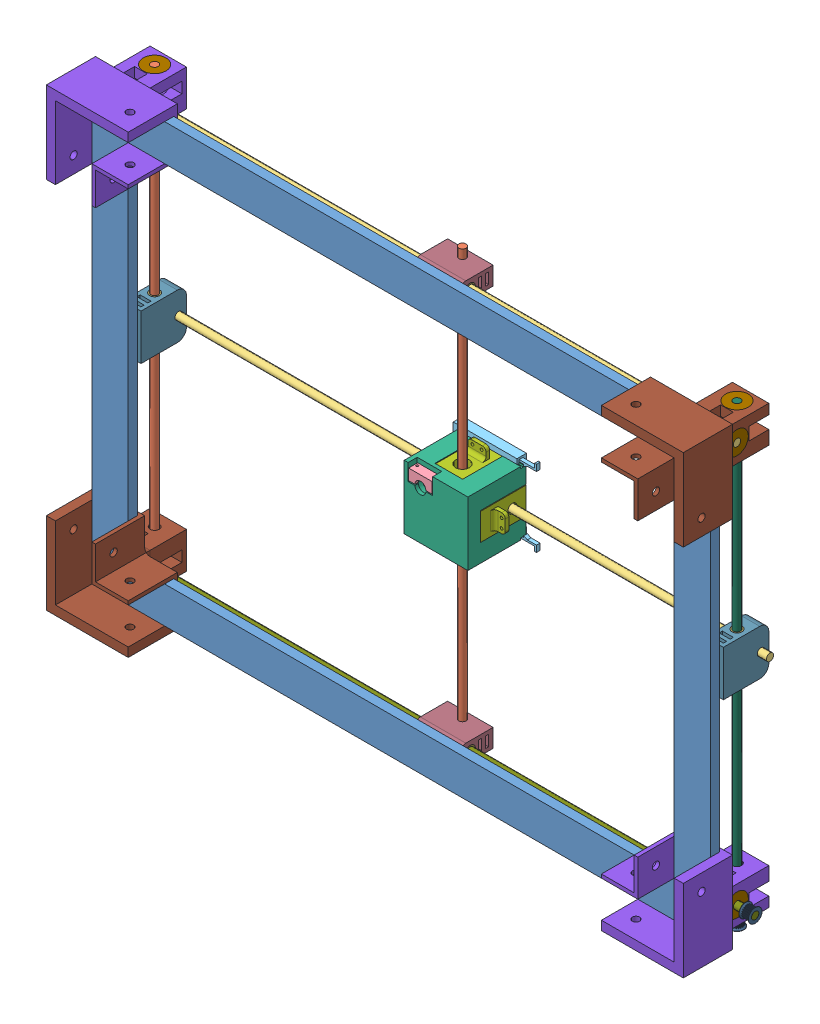
SolidWorks assembly Assemblage_XY, configuration Défaut. Lengths in mm.
Overall size (711.34 510 125.29).
50 component instances, 16 part files, 70 mates.
Components (placement in the parent):
- Cadre_XY-1: Cadre_XY [Défaut] at (379.0068 -247.2078 675) size (680 480 10)
- AXE_8X480-2: AXE_8X480 [Défaut] at (-280.9932 -247.2078 636) x (0.987721 0 0.156231) z (0 1 0) size (8 8 480)
- AXE_8X680-1: AXE_8X680 [Défaut] at (379.0068 212.7922 656) x (0 0.013067 0.999915) z (-1 0 0) size (8 8 680)
- AXE_8X480-3: AXE_8X480 [Défaut] at (60.9851 232.7922 639.7) x (0.999527 0 0.030742) z (0 -1 0) size (8 8 480)
- AXE_8X680-3: AXE_8X680 [Défaut] at (-300.9932 -9.5149 619.7) x (0 -0.696158 -0.717888) z (1 0 0) size (8 8 680)
- P3DMIPC-Tête_complete-1: P3DMIPC-Tête_complete [Défaut] at (16.7924 3.8551 635.2981) x (0 1 0) z (1 0 0) size (94 69 96.37)
  - P3DMIPC-Clip_Buse_E3D-1: P3DMIPC-Clip_Buse_E3D [Défaut] at (17.0518 23.4109 40.0035) x (1 0 0) z (0 1 0) size (12 26 10)
  - P3DMIPC-Clip_tête-1: P3DMIPC-Clip_tête [Défaut] at (26.9018 -25.0891 4.5597) x (1 0 0) z (0 -1 0) size (84 89 10.5)
  - P3DMIPC-Porte_Buse_E3DX1-1: P3DMIPC-Porte_Buse_E3DX1 [Défaut] at (22.03 33.4019 79.1927) x (0 0 1) z (0 -1 0) size (70 70 64)
  - P3DMIPC-Chariot-1: P3DMIPC-Chariot [Défaut] at (-48.37 -30.5981 79.1927) size (94 50 94)
- Angle_magique_G-1: Angle_magique_G [Défaut] at (379.0068 -247.2078 675) x (-1 0 0) z (0 0 -1) size (91.34 90 104)
- F608ZZ-1: F608ZZ [Défaut] at (372.0068 -227.2078 656) x (0 -0.924225 -0.381849) z (1 0 0) size (25 25 7)
- Angle_magique_G-4: Angle_magique_G [Défaut] at (-300.9932 232.7922 675) x (1 0 0) z (0 0 -1) size (91.34 90 104)
- pulley_gt2_3mm_20t-10: pulley_gt2_3mm_20t [Défaut] at (-280.9932 209.5422 636) x (0.106795 0 0.994281) z (0 1 0) size (15 15 10.5)
- pulley_gt2_3mm_20t-11: pulley_gt2_3mm_20t [Défaut] at (-277.7432 212.7922 656) x (0 0.106795 0.994281) z (-1 0 0) size (15 15 10.5)
- pulley_gt2_3mm_20t-12: pulley_gt2_3mm_20t [Défaut] at (-280.9932 -236.4578 636) x (-0.771074 0 0.636745) z (0 1 0) size (15 15 10.5)
- pulley_gt2_3mm_20t-13: pulley_gt2_3mm_20t [Défaut] at (-277.7432 -227.2078 656) x (0 0.106795 0.994281) z (-1 0 0) size (15 15 10.5)
- pulley_gt2_3mm_20t-15: pulley_gt2_3mm_20t [Défaut] at (359.0068 222.0422 636) x (-0.106795 0 0.994281) z (0 -1 0) size (15 15 10.5)
- pulley_gt2_3mm_20t-16: pulley_gt2_3mm_20t [Défaut] at (368.2568 212.7922 656) x (0 0.106795 0.994281) z (-1 0 0) size (15 15 10.5)
- F608ZZ-2: F608ZZ [Défaut] at (-280.9932 225.7922 636) x (-0.546944 0 0.837169) z (0 1 0) size (25 25 7)
- F608ZZ-3: F608ZZ [Défaut] at (-293.9932 212.7922 656) x (0 0 1) z (-1 0 0) size (25 25 7)
- F608ZZ-4: F608ZZ [Défaut] at (-293.9932 -227.2078 656) x (0 0 1) z (-1 0 0) size (25 25 7)
- F608ZZ-5: F608ZZ [Défaut] at (-280.9932 -240.2078 636) x (-0.924225 0 -0.381849) z (0 -1 0) size (25 25 7)
- F608ZZ-6: F608ZZ [Défaut] at (359.0068 -240.2078 636) x (-0.546944 0 0.837169) z (0 -1 0) size (25 25 7)
- F608ZZ-7: F608ZZ [Défaut] at (372.0068 212.7922 656) x (0 0 1) z (1 0 0) size (25 25 7)
- F608ZZ-8: F608ZZ [Défaut] at (359.0068 225.7922 636) x (0 0 1) z (0 1 0) size (25 25 7)
- Angle_magique_D-1: Angle_magique_D [Défaut] at (-300.9932 -247.2078 675) x (0 1 0) z (0 0 -1) size (90 91.34 104)
- Angle_magique_D-2: Angle_magique_D [Défaut] at (379.0068 232.7922 675) x (0 -1 0) z (0 0 -1) size (90 91.34 104)
- Assemblage_glissière_block_belt_palier_AR-1: Assemblage_glissière_block_belt_palier_AR [Défaut] at (181.51 -186.4667 609.4689) x (0 -1 0) z (-1 0 0) size (20 35 50)
  - ultimaker_cuivre_fritté_douille_8mmx11mmx22 mm-1: ultimaker_cuivre_fritté_douille_8mmx11mmx22 mm [Défaut] at (40.7411 46.5311 95.5249) size (11 11 22)
  - ultimaker_cuivre_fritté_douille_8mmx11mmx22 mm-2: ultimaker_cuivre_fritté_douille_8mmx11mmx22 mm [Défaut] at (40.7411 46.5311 123.5249) size (11 11 22)
  - Glisière_block_belt_AR-2: Glisière_block_belt_AR [Défaut] at (50.7411 14.5311 95.5249) size (20 35 50)
- Assemblage_glissière_block_belt_palier_AR-2: Assemblage_glissière_block_belt_palier_AR [Défaut] at (-59.5398 172.0511 609.4689) x (0 1 0) z (1 0 0) size (20 35 50)
  - ultimaker_cuivre_fritté_douille_8mmx11mmx22 mm-1: ultimaker_cuivre_fritté_douille_8mmx11mmx22 mm [Défaut] at (40.7411 46.5311 95.5249) size (11 11 22)
  - ultimaker_cuivre_fritté_douille_8mmx11mmx22 mm-2: ultimaker_cuivre_fritté_douille_8mmx11mmx22 mm [Défaut] at (40.7411 46.5311 123.5249) size (11 11 22)
  - Glisière_block_belt_AR-2: Glisière_block_belt_AR [Défaut] at (50.7411 14.5311 95.5249) size (20 35 50)
- pulley_gt2_3mm_20t-17: pulley_gt2_3mm_20t [Défaut] at (368.2568 -227.2078 656) x (0 0.106795 0.994281) z (-1 0 0) size (15 15 10.5)
- pulley_gt2_3mm_20t-18: pulley_gt2_3mm_20t [Défaut] at (359.0068 -223.9578 636) x (0.203502 0 0.979074) z (0 -1 0) size (15 15 10.5)
- Assemblage_glissière_block_belt_palier_GD-1: Assemblage_glissière_block_belt_palier_GD [Défaut] at (364.4936 -84.5149 631.6132) x (-1 0 0) z (0 1 0) size (20 50 50)
  - Glisière_block_belt_GD-1: Glisière_block_belt_GD [Défaut] at (15.4869 -20.6132 50) size (20 50 50)
  - ultimaker_cuivre_fritté_douille_8mmx11mmx22 mm-1: ultimaker_cuivre_fritté_douille_8mmx11mmx22 mm [Défaut] at (5.4869 4.3868 50) size (11 11 22)
  - ultimaker_cuivre_fritté_douille_8mmx11mmx22 mm-2: ultimaker_cuivre_fritté_douille_8mmx11mmx22 mm [Défaut] at (5.4869 4.3868 78) size (11 11 22)
- Assemblage_glissière_block_belt_palier_GD-2: Assemblage_glissière_block_belt_palier_GD [Défaut] at (-286.4801 65.4851 631.6132) x (1 0 0) z (0 -1 0) size (20 50 50)
  - Glisière_block_belt_GD-1: Glisière_block_belt_GD [Défaut] at (15.4869 -20.6132 50) size (20 50 50)
  - ultimaker_cuivre_fritté_douille_8mmx11mmx22 mm-1: ultimaker_cuivre_fritté_douille_8mmx11mmx22 mm [Défaut] at (5.4869 4.3868 50) size (11 11 22)
  - ultimaker_cuivre_fritté_douille_8mmx11mmx22 mm-2: ultimaker_cuivre_fritté_douille_8mmx11mmx22 mm [Défaut] at (5.4869 4.3868 78) size (11 11 22)
- AXE_8X500_Moteur-1: AXE_8X500_Moteur [Défaut] at (359.0068 -267.2078 636) x (0.283264 0 -0.959042) z (0 1 0) size (8 8 500)
- AXE_8X700_Moteur-1: AXE_8X700_Moteur [Défaut] at (399.0068 -227.2078 656) x (0 0 1) z (-1 0 0) size (8 8 700)
- pulley_gt2_3mm_20t-19: pulley_gt2_3mm_20t [Défaut] at (359.0068 -255.7078 636) x (0.203502 0 0.979074) z (0 -1 0) size (15 15 10.5)
- pulley_gt2_3mm_20t-20: pulley_gt2_3mm_20t [Défaut] at (387.5068 -227.2078 656) x (0 0.203502 0.979074) z (1 0 0) size (15 15 10.5)
Mates (geometry in assembly coordinates):
- Coaxiale1: concentric anti-aligned: cylinder of AXE_8X680-3 through (379.0068 -9.5149 619.7) axis (-1 0 0) radius 4; cylinder of P3DMIPC-Tête_complete-1/P3DMIPC-Chariot-1 through (91.9851 -9.5149 619.7) axis (1 0 0) radius 5
- Coaxiale2: concentric anti-aligned: cylinder of AXE_8X480-3 through (60.9851 -247.2078 639.7) axis (0 1 0) radius 4; cylinder of P3DMIPC-Tête_complete-1/P3DMIPC-Chariot-1 through (60.9851 -40.5149 639.7) axis (0 -1 0) radius 5
- Coïncidente14: coincident anti-aligned: plane of Cadre_XY-1 through (379.0068 -247.2078 675) normal (0 0 -1); plane of Angle_magique_G-1 through (379.0068 -247.2078 675) normal (0 0 1)
- Coïncidente15: coincident anti-aligned: plane of Cadre_XY-1 through (379.0068 -247.2078 685) normal (1 0 0); plane of Angle_magique_G-1 through (379.0068 -247.2078 725) normal (-1 0 0)
- Coïncidente16: coincident anti-aligned: plane of Cadre_XY-1 through (379.0068 -247.2078 685) normal (0 -1 0); plane of Angle_magique_G-1 through (299.0068 -247.2078 725) normal (0 1 0)
- Coïncidente27: coincident anti-aligned: plane of Cadre_XY-1 through (379.0068 -247.2078 675) normal (0 0 -1); plane of Angle_magique_G-4 through (-300.9932 232.7922 675) normal (0 0 1)
- Coïncidente28: coincident anti-aligned: plane of Cadre_XY-1 through (379.0068 232.7922 685) normal (0 1 0); plane of Angle_magique_G-4 through (-220.9932 232.7922 725) normal (0 -1 0)
- Coïncidente29: coincident anti-aligned: plane of Cadre_XY-1 through (-300.9932 -247.2078 685) normal (-1 0 0); plane of Angle_magique_G-4 through (-300.9932 232.7922 725) normal (1 0 0)
- Coaxiale17: concentric anti-aligned: cylinder of AXE_8X680-1 through (-300.9932 212.7922 656) axis (1 0 0) radius 4; cylinder of pulley_gt2_3mm_20t-11 through (-277.7432 212.7922 656) axis (-1 0 0) radius 4
- Coaxiale18: concentric aligned: cylinder of AXE_8X680-1 through (-300.9932 212.7922 656) axis (1 0 0) radius 4; cylinder of Angle_magique_G-4 through (-310.9932 212.7922 656) axis (1 0 0) radius 5
- Coïncidente30: coincident aligned: plane of Cadre_XY-1 through (-300.9932 -247.2078 685) normal (-1 0 0); plane of AXE_8X680-1 through (-300.9932 212.7922 656) normal (-1 0 0)
- Distance2: distance = 2.75 mm anti-aligned: plane of pulley_gt2_3mm_20t-11 through (-278.7432 212.7922 656) normal (1 0 0); plane of Angle_magique_G-4 through (-275.9932 192.7922 621) normal (-1 0 0)
- Coaxiale19: concentric anti-aligned: cylinder of AXE_8X680-1 through (-300.9932 212.7922 656) axis (1 0 0) radius 4; cylinder of pulley_gt2_3mm_20t-16 through (368.2568 212.7922 656) axis (-1 0 0) radius 4
- Coaxiale24: concentric aligned: cylinder of AXE_8X480-2 through (-280.9932 232.7922 636) axis (0 -1 0) radius 4; cylinder of Angle_magique_G-4 through (-280.9932 232.7923 636) axis (0 -1 0) radius 5
- Coaxiale25: concentric anti-aligned: cylinder of AXE_8X480-2 through (-280.9932 232.7922 636) axis (0 -1 0) radius 4; cylinder of pulley_gt2_3mm_20t-10 through (-280.9932 209.5422 636) axis (0 1 0) radius 4
- Coïncidente34: coincident aligned: plane of Cadre_XY-1 through (379.0068 232.7922 685) normal (0 1 0); plane of AXE_8X480-2 through (-280.9932 232.7922 636) normal (0 1 0)
- Distance4: distance = 2.75 mm anti-aligned: plane of pulley_gt2_3mm_20t-10 through (-280.9932 210.5422 636) normal (0 -1 0); plane of Angle_magique_G-4 through (-275.9932 207.7922 621) normal (0 1 0)
- Coaxiale26: concentric anti-aligned: cylinder of AXE_8X480-2 through (-280.9932 232.7922 636) axis (0 -1 0) radius 4; cylinder of pulley_gt2_3mm_20t-12 through (-280.9932 -236.4578 636) axis (0 1 0) radius 4
- Coïncidente44: coincident anti-aligned: plane of Cadre_XY-1 through (379.0068 -247.2078 675) normal (0 0 -1); plane of Angle_magique_D-1 through (-300.9932 -247.2078 675) normal (0 0 1)
- Coïncidente45: coincident anti-aligned: plane of Cadre_XY-1 through (379.0068 -247.2078 685) normal (0 -1 0); plane of Angle_magique_D-1 through (-300.9932 -247.2078 725) normal (0 1 0)
- Coïncidente46: coincident anti-aligned: plane of Cadre_XY-1 through (-300.9932 -247.2078 685) normal (-1 0 0); plane of Angle_magique_D-1 through (-300.9932 -167.2078 725) normal (1 0 0)
- Distance10: distance = 2.75 mm anti-aligned: plane of Angle_magique_D-1 through (-260.9932 -222.2078 621) normal (0 -1 0); plane of pulley_gt2_3mm_20t-12 through (-280.9932 -224.9578 636) normal (0 1 0)
- Coïncidente51: coincident anti-aligned: plane of Cadre_XY-1 through (379.0068 -247.2078 675) normal (0 0 -1); plane of Angle_magique_D-2 through (379.0068 232.7922 675) normal (0 0 1)
- Coïncidente52: coincident anti-aligned: plane of Cadre_XY-1 through (379.0068 232.7922 685) normal (0 1 0); plane of Angle_magique_D-2 through (379.0068 232.7922 725) normal (0 -1 0)
- Coïncidente53: coincident anti-aligned: plane of Cadre_XY-1 through (379.0068 -247.2078 685) normal (1 0 0); plane of Angle_magique_D-2 through (379.0068 152.7922 725) normal (-1 0 0)
- Distance11: distance = 2.75 mm anti-aligned: plane of pulley_gt2_3mm_20t-15 through (359.0068 210.5422 636) normal (0 -1 0); plane of Angle_magique_D-2 through (339.0068 207.7922 621) normal (0 1 0)
- Distance12: distance = 2.75 mm anti-aligned: plane of Angle_magique_D-2 through (354.0068 207.7922 621) normal (1 0 0); plane of pulley_gt2_3mm_20t-16 through (356.7568 212.7922 656) normal (-1 0 0)
- Coaxiale39: concentric anti-aligned: cylinder of AXE_8X680-1 through (-300.9932 212.7922 656) axis (1 0 0) radius 4; cylinder of Assemblage_glissière_block_belt_palier_AR-2/ultimaker_cuivre_fritté_douille_8mmx11mmx22 mm-1 through (57.9851 212.7922 656) axis (-1 0 0) radius 4
- Coaxiale42: concentric anti-aligned: cylinder of AXE_8X480-3 through (60.9851 -247.2078 639.7) axis (0 1 0) radius 4; cylinder of Assemblage_glissière_block_belt_palier_AR-2/Glisière_block_belt_AR-2 through (60.9851 222.7922 639.7) axis (0 -1 0) radius 4
- Coaxiale43: concentric aligned: cylinder of AXE_8X480-3 through (60.9851 -247.2078 639.7) axis (0 1 0) radius 4; cylinder of Assemblage_glissière_block_belt_palier_AR-1/Glisière_block_belt_AR-2 through (60.9851 -237.2078 639.7) axis (0 1 0) radius 4
- Coaxiale50: concentric anti-aligned: cylinder of F608ZZ-7 through (377.5068 212.7922 656) axis (-1 0 0) radius 11; cylinder of Angle_magique_D-2 through (372.0068 212.7922 656) axis (1 0 0) radius 11
- Coïncidente63: coincident anti-aligned: plane of F608ZZ-7 through (372.0068 212.7922 656) normal (-1 0 0); plane of Angle_magique_D-2 through (372.0068 212.7922 656) normal (1 0 0)
- Coaxiale51: concentric anti-aligned: cylinder of F608ZZ-8 through (359.0068 231.2922 636) axis (0 -1 0) radius 11; cylinder of Angle_magique_D-2 through (359.0068 225.7922 636) axis (0 1 0) radius 11
- Coïncidente64: coincident anti-aligned: plane of F608ZZ-8 through (359.0068 225.7922 636) normal (0 -1 0); plane of Angle_magique_D-2 through (359.0068 225.7922 636) normal (0 1 0)
- Coïncidente65: coincident anti-aligned: plane of Angle_magique_G-4 through (-280.9932 225.7922 636) normal (0 1 0); plane of F608ZZ-2 through (-280.9932 225.7922 636) normal (0 -1 0)
- Coaxiale53: concentric anti-aligned: cylinder of Angle_magique_G-4 through (-280.9932 225.7922 636) axis (0 1 0) radius 11; cylinder of F608ZZ-2 through (-280.9932 231.2922 636) axis (0 -1 0) radius 11
- Coaxiale54: concentric anti-aligned: cylinder of Angle_magique_G-4 through (-293.9932 212.7922 656) axis (-1 0 0) radius 11; cylinder of F608ZZ-3 through (-299.4932 212.7922 656) axis (1 0 0) radius 11
- Coïncidente66: coincident anti-aligned: plane of Angle_magique_G-4 through (-293.9932 212.7922 656) normal (-1 0 0); plane of F608ZZ-3 through (-293.9932 212.7922 656) normal (1 0 0)
- Coaxiale57: concentric anti-aligned: cylinder of F608ZZ-4 through (-299.4932 -227.2078 656) axis (1 0 0) radius 11; cylinder of Angle_magique_D-1 through (-293.9932 -227.2078 656) axis (-1 0 0) radius 11
- Coïncidente69: coincident anti-aligned: plane of F608ZZ-4 through (-293.9932 -227.2078 656) normal (1 0 0); plane of Angle_magique_D-1 through (-293.9932 -227.2078 656) normal (-1 0 0)
- Coïncidente70: coincident anti-aligned: plane of F608ZZ-5 through (-280.9932 -240.2078 636) normal (0 1 0); plane of Angle_magique_D-1 through (-280.9932 -240.2078 636) normal (0 -1 0)
- Coaxiale58: concentric anti-aligned: cylinder of F608ZZ-5 through (-280.9932 -245.7078 636) axis (0 1 0) radius 11; cylinder of Angle_magique_D-1 through (-280.9932 -240.2078 636) axis (0 -1 0) radius 11
- Distance14: distance = 2.75 mm anti-aligned: plane of Angle_magique_G-1 through (354.0068 -222.2078 621) normal (0 -1 0); plane of pulley_gt2_3mm_20t-18 through (359.0068 -224.9578 636) normal (0 1 0)
- Distance15: distance = 2.75 mm anti-aligned: plane of Angle_magique_G-1 through (354.0068 -207.2078 621) normal (1 0 0); plane of pulley_gt2_3mm_20t-17 through (356.7568 -227.2078 656) normal (-1 0 0)
- Coïncidente73: coincident anti-aligned: plane of Angle_magique_G-1 through (359.0068 -240.2078 636) normal (0 -1 0); plane of F608ZZ-6 through (359.0068 -240.2078 636) normal (0 1 0)
- Coaxiale61: concentric anti-aligned: cylinder of Angle_magique_G-1 through (359.0068 -240.2078 636) axis (0 -1 0) radius 11; cylinder of F608ZZ-6 through (359.0068 -245.7078 636) axis (0 1 0) radius 11
- Coïncidente74: coincident anti-aligned: plane of Angle_magique_G-1 through (372.0068 -227.2078 656) normal (1 0 0); plane of F608ZZ-1 through (372.0068 -227.2078 656) normal (-1 0 0)
- Coaxiale62: concentric anti-aligned: cylinder of Angle_magique_G-1 through (372.0068 -227.2078 656) axis (1 0 0) radius 11; cylinder of F608ZZ-1 through (377.5068 -227.2078 656) axis (-1 0 0) radius 11
- Coaxiale64: concentric anti-aligned: cylinder of AXE_8X680-3 through (379.0068 -9.5149 619.7) axis (-1 0 0) radius 4; cylinder of Assemblage_glissière_block_belt_palier_GD-1/Glisière_block_belt_GD-1 through (349.0068 -9.5149 619.7) axis (1 0 0) radius 4
- Coaxiale65: concentric anti-aligned: cylinder of Assemblage_glissière_block_belt_palier_GD-2/ultimaker_cuivre_fritté_douille_8mmx11mmx22 mm-1 through (-280.9932 -6.5149 636) axis (0 1 0) radius 4; cylinder of AXE_8X480-2 through (-280.9932 232.7922 636) axis (0 -1 0) radius 4
- Coaxiale66: concentric aligned: cylinder of AXE_8X680-3 through (379.0068 -9.5149 619.7) axis (-1 0 0) radius 4; cylinder of Assemblage_glissière_block_belt_palier_GD-2/Glisière_block_belt_GD-1 through (-270.9932 -9.5149 619.7) axis (-1 0 0) radius 4
- Coïncidente75: coincident aligned: plane of Cadre_XY-1 through (-300.9932 -247.2078 685) normal (-1 0 0); plane of AXE_8X680-3 through (-300.9932 -9.5149 619.7) normal (-1 0 0)
- Coïncidente76: coincident aligned: plane of Cadre_XY-1 through (379.0068 -247.2078 685) normal (0 -1 0); plane of AXE_8X480-3 through (60.9851 -247.2078 639.7) normal (0 -1 0)
- Distance17: distance = 2.75 mm anti-aligned: plane of pulley_gt2_3mm_20t-13 through (-278.7432 -227.2078 656) normal (1 0 0); plane of Angle_magique_D-1 through (-275.9932 -222.2078 621) normal (-1 0 0)
- Coaxiale67: concentric anti-aligned: cylinder of Angle_magique_G-1 through (389.0068 -227.2078 656) axis (-1 0 0) radius 5; cylinder of AXE_8X700_Moteur-1 through (-300.9932 -227.2078 656) axis (1 0 0) radius 4
- Coaxiale68: concentric aligned: cylinder of Assemblage_glissière_block_belt_palier_AR-1/ultimaker_cuivre_fritté_douille_8mmx11mmx22 mm-2 through (35.9851 -227.2078 656) axis (1 0 0) radius 4; cylinder of AXE_8X700_Moteur-1 through (-300.9932 -227.2078 656) axis (1 0 0) radius 4
- Coaxiale69: concentric aligned: cylinder of Angle_magique_D-1 through (-310.9932 -227.2078 656) axis (1 0 0) radius 5; cylinder of AXE_8X700_Moteur-1 through (-300.9932 -227.2078 656) axis (1 0 0) radius 4
- Coïncidente80: coincident aligned: plane of Cadre_XY-1 through (-300.9932 -247.2078 685) normal (-1 0 0); plane of AXE_8X700_Moteur-1 through (-300.9932 -227.2078 656) normal (-1 0 0)
- Coaxiale70: concentric anti-aligned: cylinder of pulley_gt2_3mm_20t-13 through (-277.7432 -227.2078 656) axis (-1 0 0) radius 4; cylinder of AXE_8X700_Moteur-1 through (-300.9932 -227.2078 656) axis (1 0 0) radius 4
- Coaxiale71: concentric anti-aligned: cylinder of pulley_gt2_3mm_20t-17 through (368.2568 -227.2078 656) axis (-1 0 0) radius 4; cylinder of AXE_8X700_Moteur-1 through (-300.9932 -227.2078 656) axis (1 0 0) radius 4
- Coaxiale72: concentric aligned: cylinder of Assemblage_glissière_block_belt_palier_GD-1/ultimaker_cuivre_fritté_douille_8mmx11mmx22 mm-2 through (359.0068 15.4851 636) axis (0 -1 0) radius 4; cylinder of AXE_8X500_Moteur-1 through (359.0068 232.7922 636) axis (0 -1 0) radius 4
- Coaxiale73: concentric anti-aligned: cylinder of Angle_magique_G-1 through (359.0068 -247.2078 636) axis (0 1 0) radius 5; cylinder of AXE_8X500_Moteur-1 through (359.0068 232.7922 636) axis (0 -1 0) radius 4
- Coaxiale74: concentric aligned: cylinder of Angle_magique_D-2 through (359.0068 242.7922 636) axis (0 -1 0) radius 5; cylinder of AXE_8X500_Moteur-1 through (359.0068 232.7922 636) axis (0 -1 0) radius 4
- Coaxiale75: concentric aligned: cylinder of pulley_gt2_3mm_20t-15 through (359.0068 222.0422 636) axis (0 -1 0) radius 4; cylinder of AXE_8X500_Moteur-1 through (359.0068 232.7922 636) axis (0 -1 0) radius 4
- Coaxiale76: concentric aligned: cylinder of pulley_gt2_3mm_20t-18 through (359.0068 -223.9578 636) axis (0 -1 0) radius 4; cylinder of AXE_8X500_Moteur-1 through (359.0068 232.7922 636) axis (0 -1 0) radius 4
- Coïncidente81: coincident aligned: plane of Cadre_XY-1 through (379.0068 232.7922 685) normal (0 1 0); plane of AXE_8X500_Moteur-1 through (359.0068 232.7922 636) normal (0 1 0)
- Coaxiale77: concentric aligned: cylinder of AXE_8X500_Moteur-1 through (359.0068 232.7922 636) axis (0 -1 0) radius 4; cylinder of pulley_gt2_3mm_20t-19 through (359.0068 -255.7078 636) axis (0 -1 0) radius 4
- Coïncidente82: coincident aligned: plane of AXE_8X500_Moteur-1 through (359.0068 -267.2078 636) normal (0 -1 0); plane of pulley_gt2_3mm_20t-19 through (359.0068 -267.2078 636) normal (0 -1 0)
- Coïncidente83: coincident aligned: plane of AXE_8X700_Moteur-1 through (399.0068 -227.2078 656) normal (1 0 0); plane of pulley_gt2_3mm_20t-20 through (399.0068 -227.2078 656) normal (1 0 0)
- Coaxiale78: concentric aligned: cylinder of AXE_8X700_Moteur-1 through (-300.9932 -227.2078 656) axis (1 0 0) radius 4; cylinder of pulley_gt2_3mm_20t-20 through (387.5068 -227.2078 656) axis (1 0 0) radius 4
